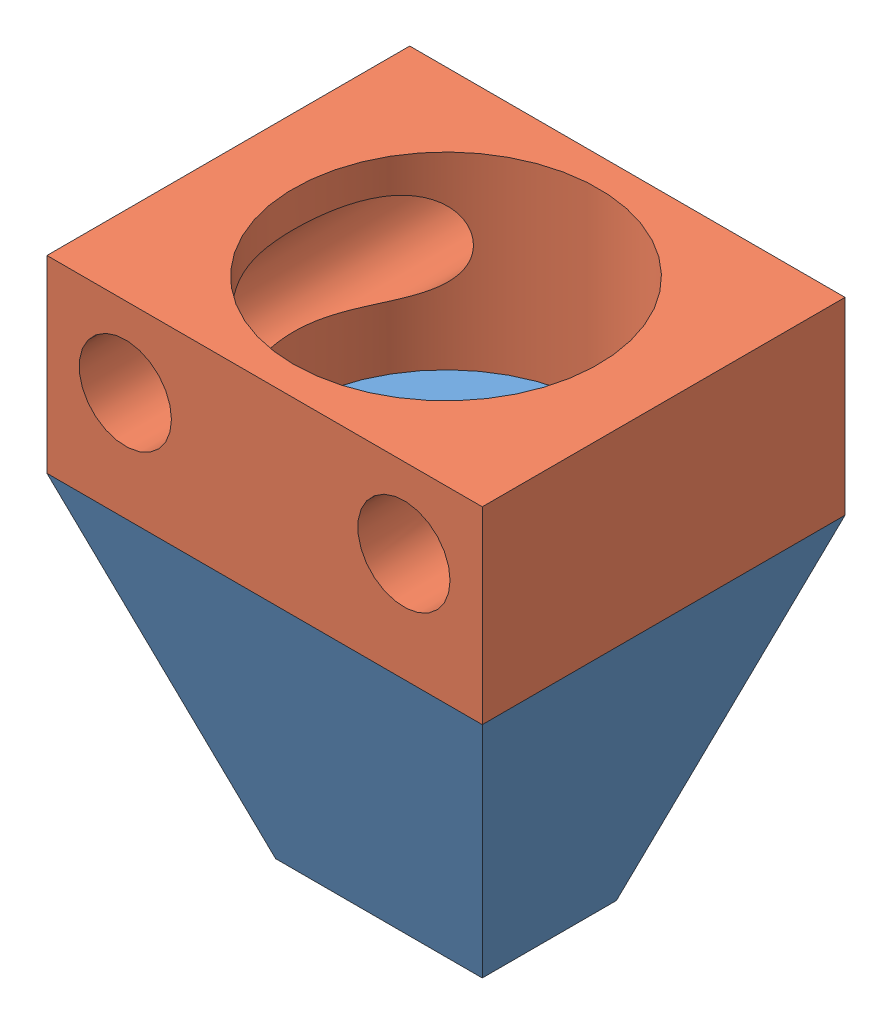
SolidWorks assembly Housing_1d, configuration Default. Lengths in mm.
Overall size (7.62 9.14 6.35).
2 component instances, 2 part files, 2 mates.
Components (placement in the parent):
- Part2b-1: Part2b [Default] at (-0.0292 -4.2206 0.8984) size (7.62 5.84 6.35)
- Part1d-1: Part1d [Default] at (-0.0292 1.6214 0.8984) size (7.62 3.3 6.35)
Mates (geometry in assembly coordinates):
- Coincident2: coincident aligned: line of Part2b-1 through (3.7808 1.6214 4.0734) axis (0 0 -1); line of Part1d-1 through (3.7808 1.6214 4.0734) axis (0 0 -1)
- Coincident3: coincident aligned: line of Part2b-1 through (-3.8392 1.6214 4.0734) axis (1 0 0); line of Part1d-1 through (-3.8392 1.6214 4.0734) axis (1 0 0)
